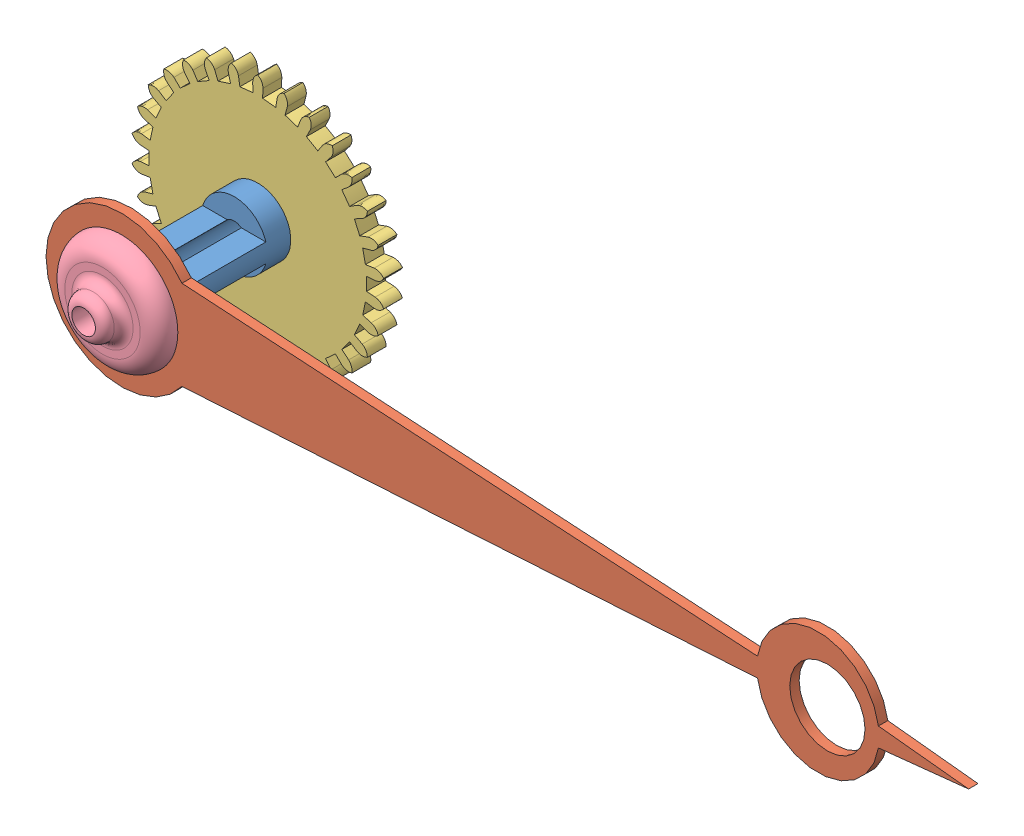
SolidWorks assembly motionwork minute assy, configuration Default. Lengths in mm.
Overall size (83.37 26.88 22).
5 component instances, 5 part files, 9 mates.
Components (placement in the parent):
- motionwork minute pipe-1: motionwork minute pipe [Default] at origin size (7 7 18)
- motionwork minute hand-1: motionwork minute hand [Default] at (0 0 3) size (78 16 1)
- motionwork minute pinion-1: motionwork minute pinion [Default] at (0 0 8.5) size (26.73 26.88 2)
- motionwork endcap-1: motionwork endcap [Default] at (0 0 23) size (12 12 4)
- motionwork minute hand support-1: motionwork minute hand support [Default] at (0 0 22) size (12 12 3)
Mates (geometry in assembly coordinates):
- Coincident1: coincident: plane of motionwork minute pipe-1 through (0 0 23) normal (0 0 1); plane of motionwork minute hand-1 through (54 0 23) normal (0 0 1)
- Concentric1: concentric: cylinder of motionwork minute pipe-1 through (0 0 23) axis (0 0 -1) radius 3.5; circle of motionwork minute hand-1
- Concentric2: concentric: cylinder of motionwork minute pipe-1 through (0 0 23) axis (0 0 -1) radius 3.5; cylinder of motionwork minute pinion-1 through (0 0 6.5) axis (0 0 1) radius 3.5
- Distance1: distance = 1.5 mm: plane of motionwork minute pipe-1 through (0 0 5) normal (0 0 -1); plane of motionwork minute pinion-1 through (-0.55 12.4879 6.5) normal (0 0 -1)
- Coincident2: coincident: plane of motionwork minute pipe-1 through (0 0 20) normal (0 0 1); plane of motionwork minute hand support-1 through (0 0 20) normal (0 0 -1)
- Concentric3: concentric: cylinder of motionwork minute hand-1 through (0 0 23) axis (0 0 -1) radius 4.5; cylinder of motionwork minute hand support-1 through (0 0 23) axis (0 0 -1) radius 4.5
- Parallel1: parallel: plane of motionwork minute pipe-1 through (2.4749 -2.4749 20) normal (1 0 0); plane of motionwork minute hand support-1 through (2.4749 2.4749 23) normal (-1 0 0)
- Coincident3: coincident: plane of motionwork endcap-1 through (0 0 23) normal (0 0 -1); plane of motionwork minute hand support-1 through (0 0 23) normal (0 0 1)
- Concentric4: concentric: cylinder of motionwork minute pipe-1 through (0 0 23) axis (0 0 -1) radius 1.25; cylinder of motionwork endcap-1 through (0 0 25) axis (0 0 -1) radius 1.25
